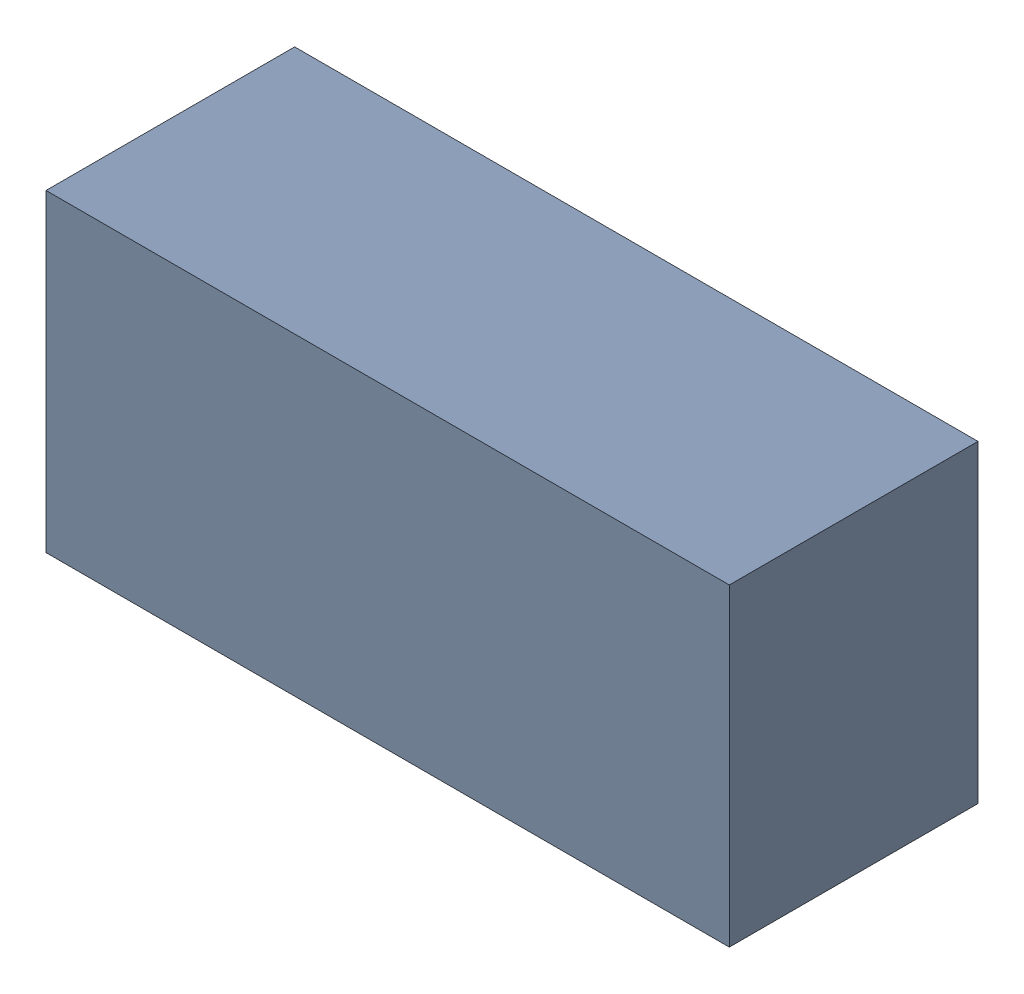
SolidWorks assembly Q400PCB, configuration Default. Lengths in mm.
Overall size (3.05 1.4 1.11).
2 component instances, 1 part files, 0 mates.
Components (placement in the parent):
- 846487368-1: 846487368 [Default] at (80.1 81.9 0.01) size (3.05 1.4 1.11)
  - Extruded_50-1: Extruded_50 [Default] at origin size (3.05 1.4 1.11)
